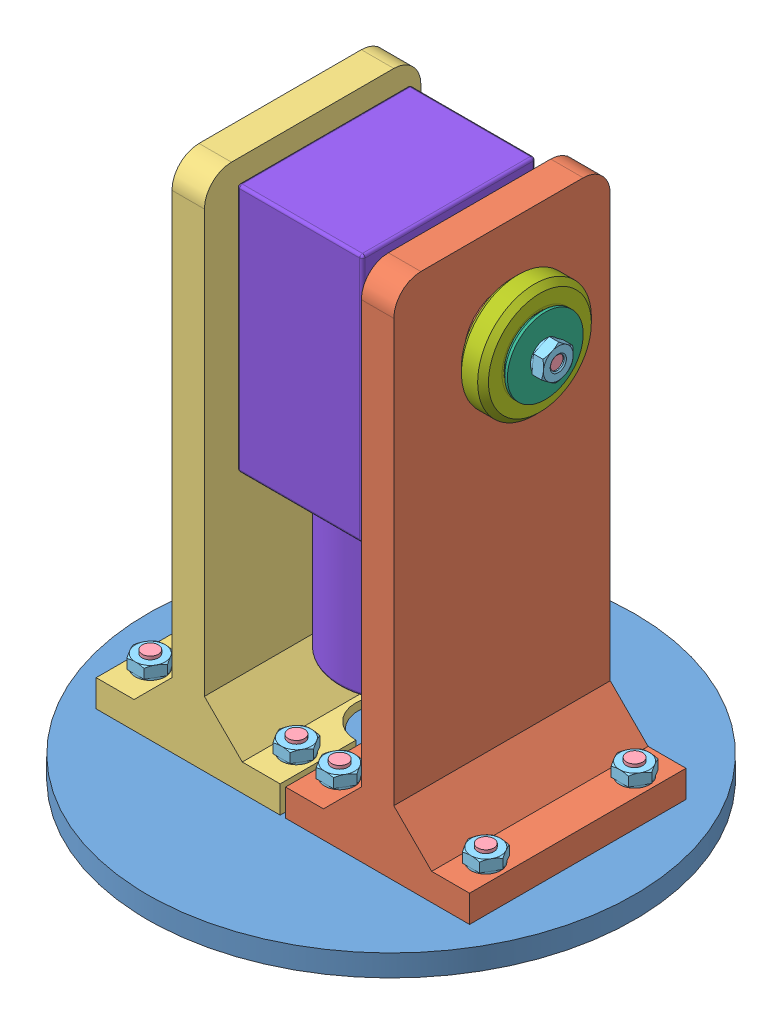
SolidWorks assembly Clamping, configuration По умолчанию. Lengths in mm.
Overall size (90 101.35 90).
34 component instances, 8 part files, 23 mates.
Components (placement in the parent):
- roundPlate-1: roundPlate [По умолчанию] at origin size (90 8 90)
- bearingClamp-1: bearingClamp [По умолчанию] at (20.5 4 0) x (0 0 1) z (0 -1 0) size (40 34 95)
- motorClamp-1: motorClamp [По умолчанию] at (-20.5 4 0) x (0 0 -1) z (0 -1 0) size (40 34 95)
- pan head cross recess screw_iso-3: pan head cross recess screw_iso [ISO 7045 - M3 x 12 - Z - 12N] at (-31 -2.4 13.5) x (0 1 0) z (-0.234156 0 0.972199) size (14.35 5.6 5.6)
- hex nut style 1 gradeab_iso-1: hex nut style 1 gradeab_iso [ISO - 4032 - M3 - W - N] at (-31 11.4 13.5) x (0 0 -1) z (0 1 0) size (5.5 6.35 2.4)
- hex nut style 1 gradeab_iso-2: hex nut style 1 gradeab_iso [ISO - 4032 - M3 - W - N] at (-31 11.4 -14) x (0 0 -1) z (0 1 0) size (5.5 6.35 2.4)
- hex nut style 1 gradeab_iso-3: hex nut style 1 gradeab_iso [ISO - 4032 - M3 - W - N] at (-4 11.4 13.5) x (0 0 -1) z (0 1 0) size (5.5 6.35 2.4)
- hex nut style 1 gradeab_iso-4: hex nut style 1 gradeab_iso [ISO - 4032 - M3 - W - N] at (-4 11.4 -14) x (0 0 -1) z (0 1 0) size (5.5 6.35 2.4)
- pan head cross recess screw_iso-4: pan head cross recess screw_iso [ISO 7045 - M3 x 12 - Z - 12N] at (-31 -2.4 -14) x (0 1 0) z (-0.234156 0 0.972199) size (14.35 5.6 5.6)
- pan head cross recess screw_iso-5: pan head cross recess screw_iso [ISO 7045 - M3 x 12 - Z - 12N] at (-4 -2.4 13.5) x (0 1 0) z (-0.234156 0 0.972199) size (14.35 5.6 5.6)
- pan head cross recess screw_iso-6: pan head cross recess screw_iso [ISO 7045 - M3 x 12 - Z - 12N] at (-4 -2.4 -14) x (0 1 0) z (-0.234156 0 0.972199) size (14.35 5.6 5.6)
- hex nut style 1 gradeab_iso-5: hex nut style 1 gradeab_iso [ISO - 4032 - M3 - W - N] at (4 11.4 13.5) x (0 0 -1) z (0 1 0) size (5.5 6.35 2.4)
- pan head cross recess screw_iso-7: pan head cross recess screw_iso [ISO 7045 - M3 x 12 - Z - 12N] at (4 -2.4 13.5) x (0 1 0) z (-0.234156 0 0.972199) size (14.35 5.6 5.6)
- hex nut style 1 gradeab_iso-6: hex nut style 1 gradeab_iso [ISO - 4032 - M3 - W - N] at (-31 11.4 -14) x (0 0 -1) z (0 1 0) size (5.5 6.35 2.4)
- hex nut style 1 gradeab_iso-7: hex nut style 1 gradeab_iso [ISO - 4032 - M3 - W - N] at (-4 11.4 13.5) x (0 0 -1) z (0 1 0) size (5.5 6.35 2.4)
- hex nut style 1 gradeab_iso-8: hex nut style 1 gradeab_iso [ISO - 4032 - M3 - W - N] at (-4 11.4 -14) x (0 0 -1) z (0 1 0) size (5.5 6.35 2.4)
- pan head cross recess screw_iso-8: pan head cross recess screw_iso [ISO 7045 - M3 x 12 - Z - 12N] at (-31 -2.4 -14) x (0 1 0) z (-0.234156 0 0.972199) size (14.35 5.6 5.6)
- pan head cross recess screw_iso-9: pan head cross recess screw_iso [ISO 7045 - M3 x 12 - Z - 12N] at (-4 -2.4 13.5) x (0 1 0) z (-0.234156 0 0.972199) size (14.35 5.6 5.6)
- pan head cross recess screw_iso-10: pan head cross recess screw_iso [ISO 7045 - M3 x 12 - Z - 12N] at (-4 -2.4 -14) x (0 1 0) z (-0.234156 0 0.972199) size (14.35 5.6 5.6)
- hex nut style 1 gradeab_iso-9: hex nut style 1 gradeab_iso [ISO - 4032 - M3 - W - N] at (4 11.4 -14) x (0 0 -1) z (0 1 0) size (5.5 6.35 2.4)
- hex nut style 1 gradeab_iso-10: hex nut style 1 gradeab_iso [ISO - 4032 - M3 - W - N] at (31 11.4 13.5) x (0 0 -1) z (0 1 0) size (5.5 6.35 2.4)
- hex nut style 1 gradeab_iso-11: hex nut style 1 gradeab_iso [ISO - 4032 - M3 - W - N] at (31 11.4 -14) x (0 0 -1) z (0 1 0) size (5.5 6.35 2.4)
- pan head cross recess screw_iso-11: pan head cross recess screw_iso [ISO 7045 - M3 x 12 - Z - 12N] at (4 -2.4 -14) x (0 1 0) z (-0.234156 0 0.972199) size (14.35 5.6 5.6)
- pan head cross recess screw_iso-12: pan head cross recess screw_iso [ISO 7045 - M3 x 12 - Z - 12N] at (31 -2.4 13.5) x (0 1 0) z (-0.234156 0 0.972199) size (14.35 5.6 5.6)
- pan head cross recess screw_iso-13: pan head cross recess screw_iso [ISO 7045 - M3 x 12 - Z - 12N] at (31 -2.4 -14) x (0 1 0) z (-0.234156 0 0.972199) size (14.35 5.6 5.6)
- Заглушка-1: Заглушка [По умолчанию] at (28.5 82 0) x (0 -0.660575 0.75076) z (0 -0.75076 -0.660575) size (14 2 14)
- подшипник-1: подшипник [По умолчанию] at (27.5 82 0) x (0 0.750606 0.66075) z (0 -0.66075 0.750606) size (21 5 21)
- pan head cross recess screw_iso-14: pan head cross recess screw_iso [ISO 7045 - M3 x 16 - Z - 16N] at (12.1 82 0) x (1 0 0) z (0 0.988556 0.150852) size (18.35 5.6 5.6)
- hex nut style 1 gradeab_iso-12: hex nut style 1 gradeab_iso [ISO - 4032 - M3 - W - N] at (30.9 82 0) x (0 0.817641 -0.575728) z (1 0 0) size (5.5 6.35 2.4)
- двигатель2-1: двигатель2 [По умолчанию] at (0.7 17.2 -2) x (0 0 -1) z (1 0 0) size (32 79.8 43.9)
- pan head cross recess screw_iso-15: pan head cross recess screw_iso [ISO 7045 - M3 x 8 - Z - 8N] at (-22.9 58 9) size (10.35 5.6 5.6)
- pan head cross recess screw_iso-16: pan head cross recess screw_iso [ISO 7045 - M3 x 8 - Z - 8N] at (-22.9 58 -9) size (10.35 5.6 5.6)
- pan head cross recess screw_iso-17: pan head cross recess screw_iso [ISO 7045 - M3 x 8 - Z - 8N] at (-22.9 91 9) size (10.35 5.6 5.6)
- pan head cross recess screw_iso-18: pan head cross recess screw_iso [ISO 7045 - M3 x 8 - Z - 8N] at (-22.9 91 -9) size (10.35 5.6 5.6)
Mates (geometry in assembly coordinates):
- Концентричный2: concentric aligned: circle of roundPlate-1; circle of bearingClamp-1
- Концентричный3: concentric aligned: circle of roundPlate-1; circle of bearingClamp-1
- Совпадение1: coincident anti-aligned: plane of roundPlate-1 through (0 4 0) normal (0 1 0); plane of bearingClamp-1 through (14.5 4 20) normal (0 -1 0)
- Концентричный4: concentric anti-aligned: circle of roundPlate-1; circle of motorClamp-1
- Концентричный5: concentric aligned: circle of roundPlate-1; circle of motorClamp-1
- Совпадение3: coincident anti-aligned: plane of roundPlate-1 through (0 4 0) normal (0 1 0); plane of motorClamp-1 through (-14.5 4 -20) normal (0 -1 0)
- Концентричный7: concentric anti-aligned: circle of motorClamp-1; circle of pan head cross recess screw_iso-3
- Совпадение4: coincident anti-aligned: plane of roundPlate-1 through (0 0 0) normal (0 -1 0); plane of pan head cross recess screw_iso-3 through (-32.4583 0 13.1488) normal (0 1 0)
- Концентричный8: concentric anti-aligned: circle of pan head cross recess screw_iso-3; circle of hex nut style 1 gradeab_iso-1
- Совпадение5: coincident anti-aligned: plane of motorClamp-1 through (-27.5 9 20) normal (0 1 0); plane of hex nut style 1 gradeab_iso-1 through (-34.1754 9 13.5) normal (0 -1 0)
- Концентричный9: concentric anti-aligned: circle of bearingClamp-1; circle of подшипник-1
- Совпадение6: coincident anti-aligned: plane of bearingClamp-1 through (22.5 82 0) normal (1 0 0); plane of подшипник-1 through (22.5 82 0) normal (-1 0 0)
- Концентричный10: concentric aligned: circle of bearingClamp-1; circle of Заглушка-1
- Совпадение7: coincident anti-aligned: plane of bearingClamp-1 through (26.5 82 0) normal (1 0 0); plane of Заглушка-1 through (26.5 82 0) normal (-1 0 0)
- Концентричный11: concentric anti-aligned: circle of Заглушка-1; circle of pan head cross recess screw_iso-14
- Совпадение8: coincident anti-aligned: plane of bearingClamp-1 through (14.5 4 0) normal (-1 0 0); plane of pan head cross recess screw_iso-14 through (14.5 82.2263 -1.4828) normal (1 0 0)
- Концентричный12: concentric anti-aligned: circle of pan head cross recess screw_iso-14; circle of hex nut style 1 gradeab_iso-12
- Совпадение10: coincident anti-aligned: plane of hex nut style 1 gradeab_iso-12 through (28.5 83.8282 2.5964) normal (-1 0 0); plane of Заглушка-1 through (28.5 82 0) normal (1 0 0)
- Совпадение11: coincident anti-aligned: plane of motorClamp-1 through (-14.5 4 0) normal (1 0 0); plane of двигатель2-1 through (-14.5 97 16) normal (-1 0 0)
- Концентричный13: concentric anti-aligned: circle of motorClamp-1; circle of двигатель2-1
- Концентричный14: concentric anti-aligned: circle of motorClamp-1; circle of двигатель2-1
- Концентричный15: concentric anti-aligned: circle of motorClamp-1; circle of pan head cross recess screw_iso-15
- Совпадение12: coincident anti-aligned: plane of motorClamp-1 through (-20.5 4 0) normal (-1 0 0); plane of pan head cross recess screw_iso-15 through (-20.5 59.5 9) normal (1 0 0)
